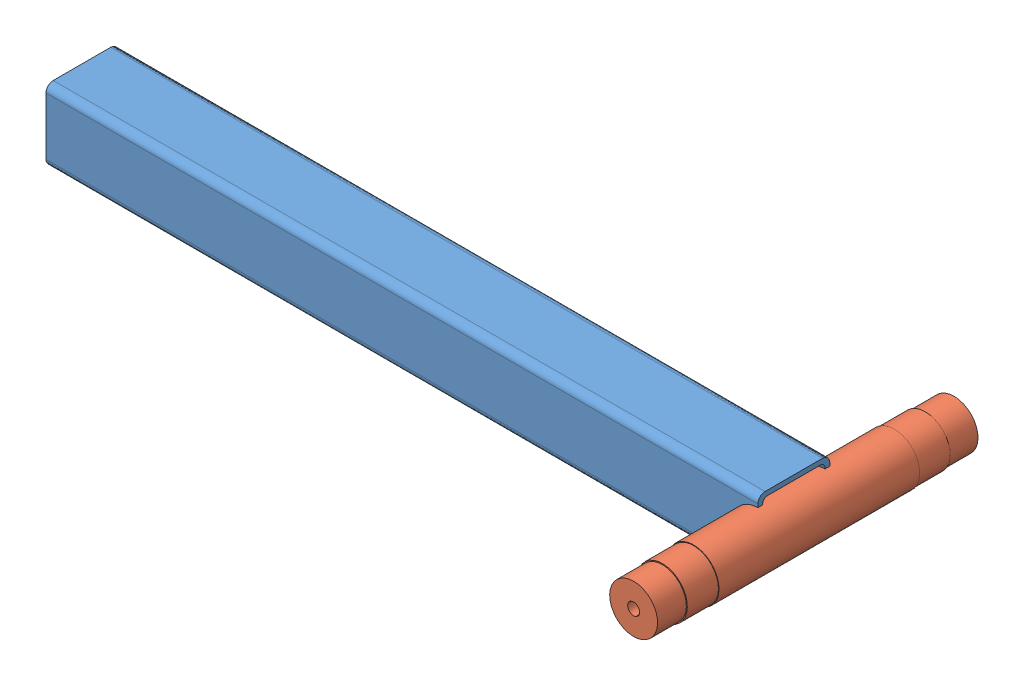
SolidWorks assembly ТП.016.02.02.01.00 - Толкатель натяжки, configuration 00. Lengths in mm.
Overall size (311.12 30 133.68).
3 component instances, 3 part files, 6 mates.
Components (placement in the parent):
- ТП.016.02.02.01.01 - Шток натяжного ролика (30х30)-1: ТП.016.02.02.01.01 - Шток натяжного ролика (30х30) [--] at origin size (297.02 30 30)
- ТП.016.02.01.01.02(02) - Ось цельная 21_3мм-1: ТП.016.02.01.01.02(02) - Ось цельная 21_3мм [--] x (0 0 1) z (-0.910058 0.41448 0) size (133.68 21.3 21.3)
- ТП.016.02.02.01.02 - Заглушка штока-1: ТП.016.02.02.01.02 - Заглушка штока [--] at (-297.0168 0 0) x (0 -1 0) z (1 0 0) size (26 26 20)
Mates (geometry in assembly coordinates):
- Концентричный1: concentric: cylinder of ТП.016.02.02.01.01 - Шток натяжного ролика (30х30)-1 through (0 0 -94.6227) axis (0 0 1) radius 10.65; cylinder of ТП.016.02.01.01.02(02) - Ось цельная 21_3мм-1 through (0 0 -66.8416) axis (0 0 -1) radius 10.65
- Совпадение1: coincident: plane of ТП.016.02.02.01.01 - Шток натяжного ролика (30х30)-1 through (0 0 0) normal (0 0 1); point of ТП.016.02.01.01.02(02) - Ось цельная 21_3мм-1
- Совпадение2: coincident: plane of ТП.016.02.02.01.01 - Шток натяжного ролика (30х30)-1 through (-297.0168 -47 12) normal (-1 0 0); plane of ТП.016.02.02.01.02 - Заглушка штока-1 through (-297.0168 0 -11) normal (-1 0 0)
- Касательность1: tangent: plane of ТП.016.02.02.01.01 - Шток натяжного ролика (30х30)-1 through (-519.4432 -13 11) normal (0 1 0); cylinder of ТП.016.02.02.01.02 - Заглушка штока-1 through (702.9832 0 0) axis (1 0 0) radius 13
- Касательность2: tangent: plane of ТП.016.02.02.01.01 - Шток натяжного ролика (30х30)-1 through (-519.4432 11 -13) normal (0 0 1); cylinder of ТП.016.02.02.01.02 - Заглушка штока-1 through (702.9832 0 0) axis (1 0 0) radius 13
- Параллельность1: parallel: plane of ТП.016.02.02.01.02 - Заглушка штока-1 through (-297.0168 0 0) normal (0 0 -1); plane of assembly through (0 0 0) normal (0 0 1)
